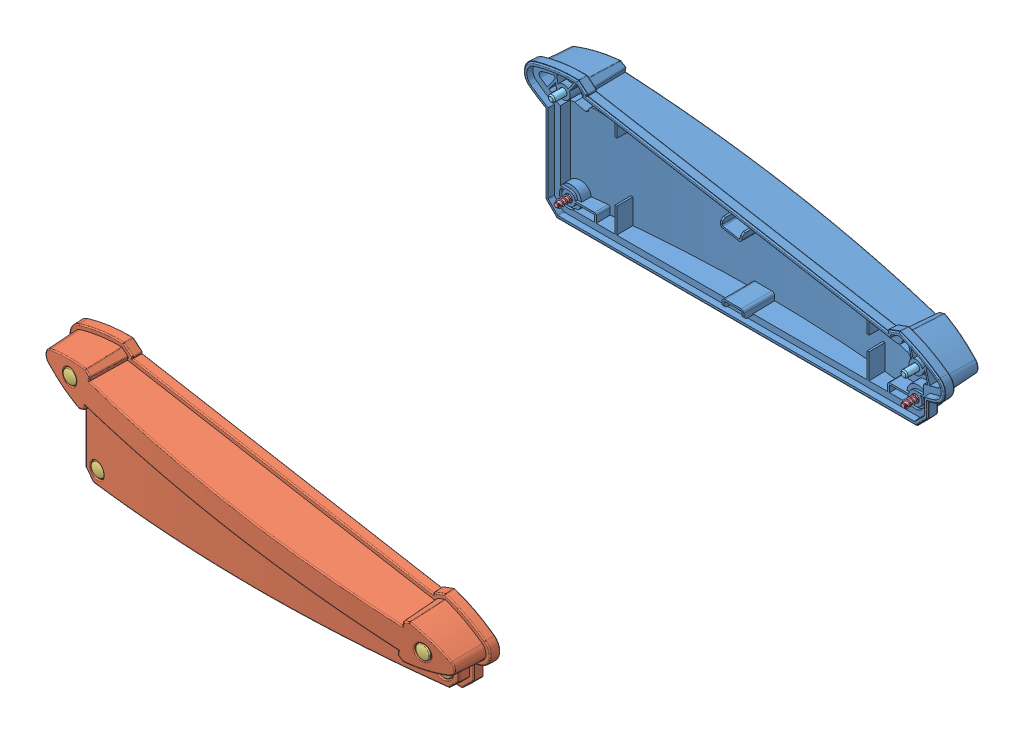
SolidWorks assembly TapaIzquierda, configuration Default. Lengths in mm.
Overall size (185.17 61.31 244.01).
19 component instances, 5 part files, 0 mates.
Components (placement in the parent):
- 92050024_ATD-1850-7024.stp-1: 92050024_ATD-1850-7024.stp [Default] at origin size (185.17 61.31 244.01)
  - 1009508_3D.stp-1: 1009508_3D.stp [Default] at origin size (185.17 61.31 26.01)
  - 1009507_3D.stp-1: 1009507_3D.stp [Default] at (0 0 200) size (185.17 57.24 26.01)
  - Abdeckstopfen_6 PART1.stp-1: Abdeckstopfen_6 PART1.stp [Default] at (76.2 -19 146.1921) x (1 0 0) z (0 -1 0) size (6.4 2.53 6.4)
  - Abdeckstopfen_6 PART1.stp-2: Abdeckstopfen_6 PART1.stp [Default] at (-76.2 -19 -150.1921) x (1 0 0) z (0 1 0) size (6.4 2.53 6.4)
  - Abdeckstopfen_6 PART1.stp-3: Abdeckstopfen_6 PART1.stp [Default] at (76.4132 -7.0663 156.1921) x (1 0 0) z (0 -1 0) size (6.4 2.53 6.4)
  - Abdeckstopfen_6 PART1.stp-4: Abdeckstopfen_6 PART1.stp [Default] at (76.2 -19 -150.1921) x (1 0 0) z (0 1 0) size (6.4 2.53 6.4)
  - Abdeckstopfen_6 PART1.stp-5: Abdeckstopfen_6 PART1.stp [Default] at (76.4132 -7.0663 -160.1921) x (1 0 0) z (0 1 0) size (6.4 2.53 6.4)
  - Abdeckstopfen_6 PART1.stp-6: Abdeckstopfen_6 PART1.stp [Default] at (-78.497 20.2486 156.1921) x (1 0 0) z (0 -1 0) size (6.4 2.53 6.4)
  - Abdeckstopfen_6 PART1.stp-7: Abdeckstopfen_6 PART1.stp [Default] at (-76.2 -19 146.1921) x (1 0 0) z (0 -1 0) size (6.4 2.53 6.4)
  - Abdeckstopfen_6 PART1.stp-8: Abdeckstopfen_6 PART1.stp [Default] at (-78.497 20.2486 -160.1921) x (1 0 0) z (0 1 0) size (6.4 2.53 6.4)
  - SHR Z KA30X8 WN 1412 MG_3DSYM.stp-1: SHR Z KA30X8 WN 1412 MG_3DSYM.stp [Default] at (-76.2 -19 -105.5) size (5.3 5.3 9.95)
  - SHR Z KA30x18x10 WN 1412 oG_3Dsym.stp-1: SHR Z KA30x18x10 WN 1412 oG_3Dsym.stp [Default] at (-90.3041 20.2486 26.1846) x (1 0 0) z (0 -1 0) size (5.3 19.95 5.3)
  - SHR Z KA30X8 WN 1412 MG_3DSYM.stp-2: SHR Z KA30X8 WN 1412 MG_3DSYM.stp [Default] at (76.2 -19 -105.5) size (5.3 5.3 9.95)
  - SHR Z KA30x18x10 WN 1412 oG_3Dsym.stp-2: SHR Z KA30x18x10 WN 1412 oG_3Dsym.stp [Default] at (-90.3041 20.2486 -30.1846) x (1 0 0) z (0 1 0) size (5.3 19.95 5.3)
  - SHR Z KA30X8 WN 1412 MG_3DSYM.stp-3: SHR Z KA30X8 WN 1412 MG_3DSYM.stp [Default] at (-76.2 -19 101.5) x (1 0 0) z (0 0 -1) size (5.3 5.3 9.95)
  - SHR Z KA30x18x10 WN 1412 oG_3Dsym.stp-3: SHR Z KA30x18x10 WN 1412 oG_3Dsym.stp [Default] at (64.6061 -7.0663 26.1846) x (1 0 0) z (0 -1 0) size (5.3 19.95 5.3)
  - SHR Z KA30X8 WN 1412 MG_3DSYM.stp-4: SHR Z KA30X8 WN 1412 MG_3DSYM.stp [Default] at (76.2 -19 101.5) x (1 0 0) z (0 0 -1) size (5.3 5.3 9.95)
  - SHR Z KA30x18x10 WN 1412 oG_3Dsym.stp-4: SHR Z KA30x18x10 WN 1412 oG_3Dsym.stp [Default] at (64.6061 -7.0663 -30.1846) x (1 0 0) z (0 1 0) size (5.3 19.95 5.3)
